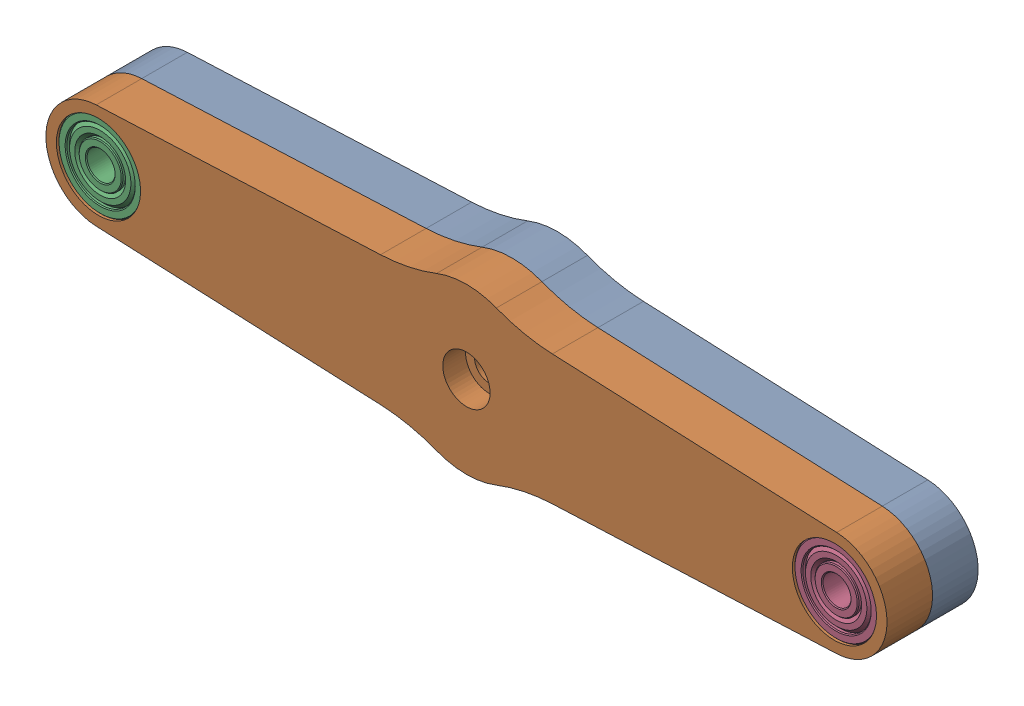
SolidWorks assembly MFG CW Aft Linkage Asmbly, configuration Default. Lengths in mm.
Overall size (240 47 26).
6 component instances, 3 part files, 0 mates.
Components (placement in the parent):
- MFG CW Aft Linkage Lower-1: MFG CW Aft Linkage Lower [Default] at origin size (240 47 13)
- MFG CW Aft Linkage Upper-1: MFG CW Aft Linkage Upper [Default] at origin size (240 47 13)
- 628Z 8x24x8mm Ball Bearing-1: 628Z 8x24x8mm Ball Bearing [Default] at (-105 29 74) size (24 24 8)
- 628Z 8x24x8mm Ball Bearing-2: 628Z 8x24x8mm Ball Bearing [Default] at (105 29 74) size (24 24 8)
- 628Z 8x24x8mm Ball Bearing-3: 628Z 8x24x8mm Ball Bearing [Default] at (105 29 58.5) size (24 24 8)
- 628Z 8x24x8mm Ball Bearing-4: 628Z 8x24x8mm Ball Bearing [Default] at (-105 29 58.5) size (24 24 8)
